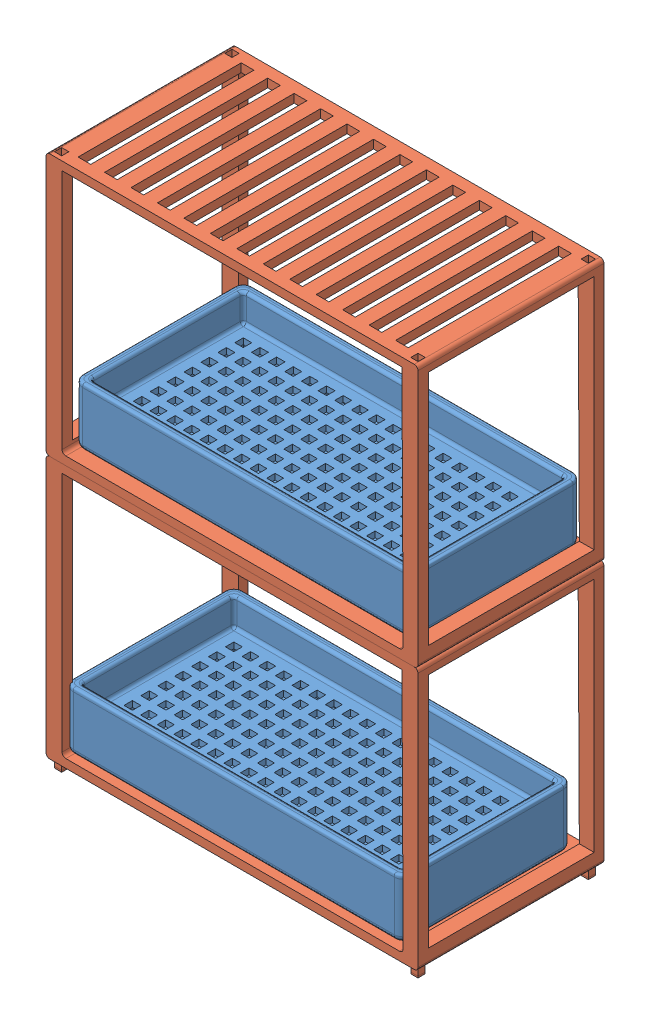
SolidWorks assembly Crate Assembly Without Lights, configuration Default. Lengths in mm.
Overall size (2200 3160.06 1100).
4 component instances, 2 part files, 3 mates.
Components (placement in the parent):
- Growing box-1: Growing box [Default] at (3745.0516 1874.7537 916.7616) size (2000.2 350.1 1000.2)
- Corn Crate-1: Corn Crate [Default] at (3868.2265 1824.7537 850.8991) size (2200 1610.06 1100)
- Corn Crate-2: Corn Crate [Default] at (3868.2265 3374.7537 850.8991) size (2200 1610.06 1100)
- Growing box-2: Growing box [Default] at (3764.7452 3424.7537 880.7881) size (2000.2 350.1 1000.2)
Mates (geometry in assembly coordinates):
- Coincident3: coincident anti-aligned: plane of Growing box-1 through (3745.0516 1874.7537 1916.7616) normal (0 -1 0); plane of Corn Crate-1 through (1763.2265 1874.7537 850.8991) normal (0 1 0)
- Coincident4: coincident: point of Corn Crate-1; point of Corn Crate-2
- Coincident5: coincident anti-aligned: plane of Corn Crate-2 through (1763.2265 3424.7537 850.8991) normal (0 1 0); plane of Growing box-2 through (3764.7452 3424.7537 1880.7881) normal (0 -1 0)
